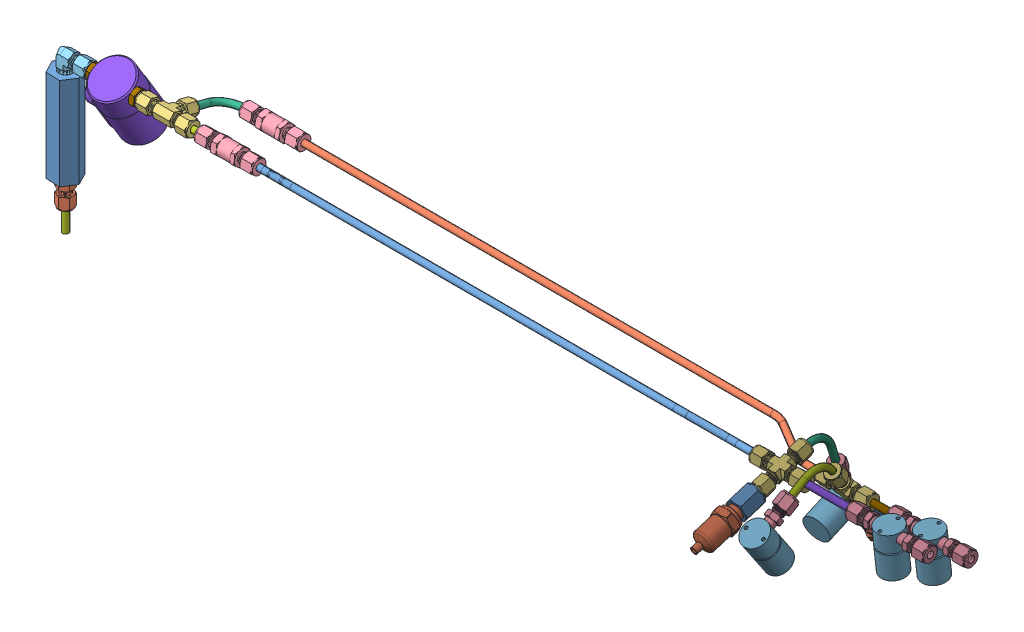
SolidWorks assembly Recovery Pneumatics, configuration Default. Lengths in mm.
Overall size (928.79 183.17 195.03).
34 component instances, 20 part files, 70 mates.
Components (placement in the parent):
- Inline Regulator-1: Inline Regulator [Default] at (0 145.161 0) x (-0.998761 0 -0.049763) z (0 -1 0) size (29.33 25.4 95.25)
- -4S -4MNPT-1: -4S -4MNPT [5182K111] at (0 22.86 0) x (0.584753 0 0.811212) z (0 -1 0) size (14.29 16.5 37.85)
- -4S Tee-1: -4S Tee [5182K434] at (78.3336 157.734 0) x (0 0.968728 -0.248124) z (-1 0 0) size (14.29 35.17 53.85)
- Check Valve -4S-2: Check Valve -4S [45385K54] at (155.8036 142.2302 -60.53) x (0 -0.278871 -0.960328) z (-1 0 0) size (15.88 18.33 60.45)
- -4S -4MNPT Elbow-3: -4S -4MNPT Elbow [5929K75] at (26.924 157.734 0) x (0 0 1) z (1 0 0) size (14.48 32.03 34.26)
- -4 Bend90 R.75 Recovery-2: -4 Bend90 R.75 Recovery [Default] at (122.7853 142.2302 -60.53) x (0 0.248124 0.968728) z (0 -0.968728 0.248124) size (53.97 38.74 6.35)
- -4 B2B Short-4: -4 B2B Short [Default] at (155.0416 157.734 0) x (0 1 0) z (0 0 1) size (6.35 38.1 6.35)
- Check Valve -4S-3: Check Valve -4S [45385K54] at (170.0276 157.734 0) x (0 0.175228 0.984528) z (-1 0 0) size (15.88 18.33 60.45)
- -4 B2B Short-5: -4 B2B Short [Default] at origin size (6.35 38.1 6.35)
- HP Solenoid -4FNPT-1: HP Solenoid -4FNPT [1190N23] at (52.6288 157.734 0) x (0 0.517885 -0.85545) z (-1 0 0) size (41.45 73.66 101.05)
- -4FS -4MNPT-1: -4FS -4MNPT [5929K622] at (11.684 157.734 0) x (0 0 1) z (-1 0 0) size (14.29 16.5 35.56)
- -4FS -4MNPT-2: -4FS -4MNPT [5929K622] at (93.5736 157.734 0) x (0 -0.924225 -0.381849) z (1 0 0) size (14.29 16.5 35.56)
- -4S -6FNPT-1: -4S -6FNPT [5182K287] at (738.088 152.0363 8.9048) x (0.794831 -0.579579 -0.179812) z (0 0.296312 -0.955091) size (19.05 22 37.77)
- PT -4MNPT-1: PT -4MNPT [Default] at (738.088 136.2926 59.6509) x (0 0.296312 -0.955091) z (-0.840318 0.517749 0.160629) size (56.32 25.42 22.23)
- -4S Cross-1: -4S Cross [5182K766] at (738.088 163.4764 -27.9694) x (0 -0.955091 -0.296312) z (0 0.296312 -0.955091) size (14.29 53.85 53.85)
- -4S -6FNPT-2: -4S -6FNPT [5182K287] at (772.5677 129.6883 -41.7795) x (0.463473 -0.49232 0.736759) z (0 0.831452 0.555596) size (19.05 22 37.77)
- PT -4MNPT-2: PT -4MNPT [Default] at (772.5677 85.5113 -71.2995) x (0 0.831452 0.555596) z (0.508115 0.478529 -0.716121) size (56.32 25.42 22.23)
- -4S Cross-2: -4S Cross [5182K766] at (772.5677 161.789 -20.329) x (0 0.555596 -0.831452) z (0 0.831452 0.555596) size (14.29 53.85 53.85)
- -4S -2MNPT-1: -4S -2MNPT [5182K807] at (810.732 155.4984 -2.2545) x (0 0 1) z (-1 0 0) size (14.29 16.5 32.77)
- Solenoid -2FNPT-1: Solenoid -2FNPT [Default] at (849.848 161.8092 -1.5493) x (0 0.111058 -0.993814) z (-1 0 0) size (25.4 43.18 25.4)
- -4 Bend90 R.75 RecovVent1-1: -4 Bend90 R.75 RecovVent1 [Default] at (738.088 164.3038 -30.6363) x (0.009447 -0.955048 -0.296299) z (0.999955 0.009023 0.002799) size (53.97 38.74 6.35)
- -4 Bend90 R.75 RecovVent2-1: -4 Bend90 R.75 RecovVent2 [Default] at (772.5677 164.1107 -18.7776) x (-0.046359 -0.554999 0.830558) z (-0.998925 0.025757 -0.038545) size (53.97 38.74 6.35)
- -4 RecovCustom1-1: -4 RecovCustom1 [Default] at (749.772 155.4984 -2.2545) x (0 -1 0) z (0 0 1) size (6.35 76.2 6.35)
- -4 RecovCustom2-1: -4 RecovCustom2 [Default] at (784.2517 139.403 -35.2879) x (0 -0.992135 0.125175) z (0 0.125175 0.992135) size (6.35 50.8 6.35)
- Solenoid -2FNPT-2: Solenoid -2FNPT [Default] at (858.9277 145.7137 -34.5826) x (0 0.111058 -0.993814) z (-1 0 0) size (25.4 43.18 25.4)
- -4S -2MNPT-2: -4S -2MNPT [5182K807] at (819.8117 139.403 -35.2879) x (0 0 1) z (-1 0 0) size (14.29 16.5 32.77)
- Solenoid -2FNPT-3: Solenoid -2FNPT [Default] at (768.9978 142.5208 56.5068) x (0.99878 -0.011601 0.047997) z (0.046359 0.554999 -0.830558) size (25.4 43.18 25.4)
- -4S -2MNPT-3: -4S -2MNPT [5182K807] at (770.9192 158.9483 20.4954) x (-0.571243 -0.667355 -0.477827) z (0.046359 0.554999 -0.830558) size (14.29 16.5 32.77)
- Solenoid -2FNPT-4: Solenoid -2FNPT [Default] at (738.2422 100.0477 -75.5468) x (-0.99618 -0.034714 0.080129) z (-0.009447 0.955048 0.296299) size (25.4 43.18 25.4)
- -4S -2MNPT-4: -4S -2MNPT [5182K807] at (738.4239 135.5359 -57.9133) x (0.766144 0.197332 -0.611623) z (-0.009447 0.955048 0.296299) size (14.29 16.5 32.77)
- -4 Recov Resevoir 1-1: -4 Recov Resevoir 1 [Default] at (200.2144 147.3252 -10.4972) x (1 0 0) z (0 0.710089 -0.704112) size (541.39 28.58 6.35)
- -4 Recov Resevoir 2-1: -4 Recov Resevoir 2 [Default] at (729.1237 139.403 -35.2879) x (1 0 0) z (0 -0.993786 -0.11131) size (590.09 31.75 6.35)
- -4S -2MNPT-5: -4S -2MNPT [5182K807] at (901.0917 139.403 -35.2879) x (0 -0.063281 -0.997996) z (1 0 0) size (14.29 16.5 32.77)
- -4S -2MNPT-6: -4S -2MNPT [5182K807] at (892.012 155.4984 -2.2545) x (0 -0.063281 -0.997996) z (1 0 0) size (14.29 16.5 32.77)
Mates (geometry in assembly coordinates):
- Distance5: distance = 6.35 mm anti-aligned: plane of InlineRegulator-1 through (0 67.056 0) normal (0 -1 0); plane of -4S -4MNPT-1 through (0 60.706 0) normal (0 1 0)
- Concentric7: concentric aligned: cylinder of InlineRegulator-1 through (0 67.056 0) axis (0 -1 0) radius 6.858; cylinder of -4S -4MNPT-1 through (0 22.86 0) axis (0 -1 0) radius 4.6228
- Distance8: distance = 6.35 mm anti-aligned: plane of -4S -4MNPT Elbow-3 through (0 134.366 0) normal (0 -1 0); plane of InlineRegulator-1 through (0 128.016 0) normal (0 1 0)
- Concentric26: concentric aligned: cylinder of InlineRegulator-1 through (0 128.016 0) axis (0 1 0) radius 6.858; cylinder of -4S -4MNPT Elbow-3 through (0 162.8866 0) axis (0 1 0) radius 4.6228
- Coincident34: coincident anti-aligned: plane of Check Valve -4S-2 through (140.8176 139.1812 -59.6446) normal (-1 0 0); plane of -4 Bend90 R.75 Recovery-2 through (140.8176 142.2302 -60.53) normal (1 0 0)
- Concentric28: concentric aligned: cylinder of Check Valve -4S-2 through (125.5776 142.2302 -60.53) axis (-1 0 0) radius 2.3749; cylinder of -4 Bend90 R.75 Recovery-2 through (140.8176 142.2302 -60.53) axis (-1 0 0) radius 2.286
- Coincident35: coincident anti-aligned: plane of -4S Tee-1 through (108.4326 154.8349 -11.3186) normal (0 -0.248124 -0.968728); plane of -4 Bend90 R.75 Recovery-2 through (105.2576 154.8349 -11.3186) normal (0 0.248124 0.968728)
- Concentric29: concentric anti-aligned: cylinder of -4S Tee-1 through (105.2576 151.0535 -26.082) axis (0 -0.248124 -0.968728) radius 2.3749; cylinder of -4 Bend90 R.75 Recovery-2 through (105.2576 146.957 -42.0757) axis (0 0.248124 0.968728) radius 2.286
- Coincident36: coincident anti-aligned: plane of -4S Tee-1 through (116.9416 158.5218 3.0757) normal (1 0 0); plane of -4 B2B Short-4 through (116.9416 157.734 0) normal (-1 0 0)
- Concentric30: concentric anti-aligned: cylinder of -4S Tee-1 through (78.3336 157.734 0) axis (-1 0 0) radius 2.3749; cylinder of -4 B2B Short-4 through (116.9416 157.734 0) axis (1 0 0) radius 2.286
- Concentric31: concentric anti-aligned: cylinder of -4 B2B Short-4 through (116.9416 157.734 0) axis (1 0 0) radius 2.286; cylinder of Check Valve -4S-3 through (139.8016 157.734 0) axis (-1 0 0) radius 2.3749
- Coincident37: coincident anti-aligned: plane of -4 B2B Short-4 through (155.0416 157.734 0) normal (1 0 0); plane of Check Valve -4S-3 through (155.0416 160.8599 -0.5563) normal (-1 0 0)
- Coincident47: coincident anti-aligned: plane of -4S -4MNPT-1 through (-2.5756 38.1 1.8566) normal (0 -1 0); plane of -4 B2B Short-5 through (0 38.1 0) normal (0 1 0)
- Concentric41: concentric aligned: cylinder of -4S -4MNPT-1 through (0 22.86 0) axis (0 -1 0) radius 2.3749; cylinder of -4 B2B Short-5 through (0 38.1 0) axis (0 -1 0) radius 2.286
- Concentric42: concentric aligned: cylinder of -4 B2B Short-5 through (0 38.1 0) axis (0 -1 0) radius 2.286
- Coincident49: coincident: plane of -4 B2B Short-5 through (0 0 0) normal (0 -1 0)
- Coincident51: coincident anti-aligned: plane of -4S -4MNPT Elbow-3 through (11.684 154.559 0) normal (1 0 0); plane of -4FS -4MNPT-1 through (11.684 157.734 0) normal (-1 0 0)
- Concentric43: concentric anti-aligned: cylinder of -4S -4MNPT Elbow-3 through (26.924 157.734 0) axis (1 0 0) radius 2.3749; cylinder of -4FS -4MNPT-1 through (11.684 157.734 0) axis (-1 0 0) radius 1.651
- Coincident52: coincident anti-aligned: plane of HP Solenoid -4FNPT-1 through (58.0136 157.734 0) normal (1 0 0); plane of -4FS -4MNPT-2 through (58.0136 157.734 0) normal (-1 0 0)
- Concentric44: concentric anti-aligned: cone of HP Solenoid -4FNPT-1 through (71.9836 157.734 0) axis (-1 0 0); cylinder of -4FS -4MNPT-2 through (93.5736 157.734 0) axis (1 0 0) radius 4.6228
- Concentric45: concentric anti-aligned: cone of HP Solenoid -4FNPT-1 through (33.274 157.734 0) axis (1 0 0); cylinder of -4FS -4MNPT-1 through (11.684 157.734 0) axis (-1 0 0) radius 4.6228
- Coincident55: coincident anti-aligned: plane of HP Solenoid -4FNPT-1 through (47.244 157.734 0) normal (-1 0 0); plane of -4FS -4MNPT-1 through (47.244 157.734 0) normal (1 0 0)
- Coincident56: coincident anti-aligned: plane of -4S Tee-1 through (93.5736 156.9462 -3.0757) normal (-1 0 0); plane of -4FS -4MNPT-2 through (93.5736 157.734 0) normal (1 0 0)
- Concentric47: concentric anti-aligned: cylinder of -4S Tee-1 through (78.3336 157.734 0) axis (-1 0 0) radius 3.175; cylinder of -4FS -4MNPT-2 through (93.5736 157.734 0) axis (1 0 0) radius 1.651
- Coincident59: coincident aligned: circle of -4S -4FNPT-1; plane of PT -4MNPT-1 through (738.088 143.9967 34.8186) normal (0 0.296312 -0.955091)
- Concentric50: concentric aligned: cylinder of -4S -6FNPT-1 through (738.088 152.0363 8.9048) axis (0 0.296312 -0.955091) radius 4.6228; cylinder of PT -4MNPT-1 through (738.088 139.552 49.1449) axis (0 0.296312 -0.955091) radius 4
- Concentric52: concentric aligned: cylinder of -4S -6FNPT-1 through (738.088 152.0363 8.9048) axis (0 0.296312 -0.955091) radius 2.3876; cylinder of -4S Cross-1 through (738.088 163.4764 -27.9694) axis (0 0.296312 -0.955091) radius 2.3749
- Coincident61: coincident anti-aligned: plane of -4S -6FNPT-1 through (738.088 152.0363 8.9048) normal (0 0.296312 -0.955091); plane of -4S Cross-1 through (741.263 152.0363 8.9048) normal (0 -0.296312 0.955091)
- Coincident65: coincident anti-aligned: plane of -4S -6FNPT-2 through (772.5677 129.6883 -41.7795) normal (0 0.831452 0.555596); plane of -4S Cross-2 through (775.7427 129.6883 -41.7795) normal (0 -0.831452 -0.555596)
- Concentric57: concentric aligned: cylinder of -4S -6FNPT-2 through (772.5677 129.6883 -41.7795) axis (0 0.831452 0.555596) radius 2.3876; cylinder of -4S Cross-2 through (772.5677 161.789 -20.329) axis (0 0.831452 0.555596) radius 2.3749
- Concentric58: concentric aligned: cylinder of -4S -6FNPT-2 through (772.5677 129.6883 -41.7795) axis (0 0.831452 0.555596) radius 4.6228; cylinder of PT -4MNPT-2 through (772.5677 94.6573 -65.188) axis (0 0.831452 0.555596) radius 4
- Coincident67: coincident aligned: circle of -4S -4FNPT-2; plane of PT -4MNPT-2 through (772.5677 107.1291 -56.854) normal (0 0.831452 0.555596)
- Coincident69: coincident anti-aligned: plane of Solenoid -2FNPT-1 through (843.498 155.4984 -2.2545) normal (-1 0 0); plane of -4S -2MNPT-1 through (843.498 155.4984 -2.2545) normal (1 0 0)
- Concentric60: concentric anti-aligned: cylinder of Solenoid -2FNPT-1 through (837.147 155.4984 -2.2545) axis (1 0 0) radius 3.175; cylinder of -4S -2MNPT-1 through (810.732 155.4984 -2.2545) axis (-1 0 0) radius 3.4163
- Coincident70: coincident anti-aligned: plane of -4S Cross-1 through (734.913 158.9606 -13.4138) normal (0 0.296312 -0.955091); plane of -4 Bend90 R.75 RecovVent1-1 through (738.088 158.9606 -13.4138) normal (0 -0.296312 0.955091)
- Concentric61: concentric aligned: cylinder of -4S Cross-1 through (738.088 163.4764 -27.9694) axis (0 0.296312 -0.955091) radius 2.3749; cylinder of -4 Bend90 R.75 RecovVent1-1 through (738.088 158.9606 -13.4138) axis (0 0.296312 -0.955091) radius 2.286
- Concentric62: concentric aligned: cylinder of -4S Cross-2 through (772.5677 161.789 -20.329) axis (0 0.831452 0.555596) radius 2.3749; cylinder of -4 Bend90 R.75 RecovVent2-1 through (772.5677 149.1177 -28.7963) axis (0 0.831452 0.555596) radius 2.286
- Coincident71: coincident anti-aligned: plane of -4S Cross-2 through (769.3927 149.1177 -28.7963) normal (0 0.831452 0.555596); plane of -4 Bend90 R.75 RecovVent2-1 through (772.5677 149.1177 -28.7963) normal (0 -0.831452 -0.555596)
- Coincident72: coincident anti-aligned: plane of -4S Cross-1 through (749.772 156.4392 -5.2869) normal (1 0 0); plane of -4 RecovCustom1-1 through (749.772 155.4984 -2.2545) normal (-1 0 0)
- Concentric63: concentric anti-aligned: cylinder of -4S Cross-1 through (765.012 155.4984 -2.2545) axis (1 0 0) radius 2.3749; cylinder of -4 RecovCustom1-1 through (825.972 155.4984 -2.2545) axis (-1 0 0) radius 2.286
- Coincident73: coincident anti-aligned: plane of -4S Cross-2 through (784.2517 142.0428 -33.5239) normal (1 0 0); plane of -4 RecovCustom2-1 through (784.2517 139.403 -35.2879) normal (-1 0 0)
- Concentric64: concentric anti-aligned: cylinder of -4S Cross-2 through (799.4917 139.403 -35.2879) axis (1 0 0) radius 2.3749; cylinder of -4 RecovCustom2-1 through (835.0517 139.403 -35.2879) axis (-1 0 0) radius 2.286
- Concentric65: concentric anti-aligned: cylinder of Solenoid -2FNPT-2 through (846.2267 139.403 -35.2879) axis (1 0 0) radius 3.175; cylinder of -4S -2MNPT-2 through (819.8117 139.403 -35.2879) axis (-1 0 0) radius 3.4163
- Coincident74: coincident anti-aligned: plane of Solenoid -2FNPT-2 through (852.5777 139.403 -35.2879) normal (-1 0 0); plane of -4S -2MNPT-2 through (852.5777 139.403 -35.2879) normal (1 0 0)
- Concentric66: concentric anti-aligned: cylinder of Solenoid -2FNPT-3 through (769.6946 144.2881 42.4346) axis (-0.046359 -0.554999 0.830558) radius 3.175; cylinder of -4S -2MNPT-3 through (770.9192 158.9483 20.4954) axis (0.046359 0.554999 -0.830558) radius 3.4163
- Coincident75: coincident anti-aligned: plane of Solenoid -2FNPT-3 through (769.4002 140.7633 47.7094) normal (0.046359 0.554999 -0.830558); plane of -4S -2MNPT-3 through (769.4002 140.7633 47.7094) normal (-0.046359 -0.554999 0.830558)
- Concentric67: concentric anti-aligned: cylinder of Solenoid -2FNPT-4 through (738.6735 110.3083 -65.74) axis (0.009447 -0.955048 -0.296299) radius 3.175; cylinder of -4S -2MNPT-4 through (738.4239 135.5359 -57.9133) axis (-0.009447 0.955048 0.296299) radius 3.4163
- Coincident76: coincident anti-aligned: plane of Solenoid -2FNPT-4 through (738.7335 104.2428 -67.6218) normal (-0.009447 0.955048 0.296299); plane of -4S -2MNPT-4 through (738.7335 104.2428 -67.6218) normal (0.009447 -0.955048 -0.296299)
- Coincident77: coincident anti-aligned: plane of -4 RecovCustom2-1 through (835.0517 139.403 -35.2879) normal (1 0 0); plane of -4S -2MNPT-2 through (835.0517 142.578 -35.2879) normal (-1 0 0)
- Concentric68: concentric aligned: cylinder of -4 RecovCustom2-1 through (835.0517 139.403 -35.2879) axis (-1 0 0) radius 2.286; cylinder of -4S -2MNPT-2 through (819.8117 139.403 -35.2879) axis (-1 0 0) radius 2.3749
- Coincident78: coincident anti-aligned: plane of -4S -2MNPT-1 through (825.972 158.6734 -2.2545) normal (-1 0 0); plane of -4 RecovCustom1-1 through (825.972 155.4984 -2.2545) normal (1 0 0)
- Concentric69: concentric aligned: cylinder of -4S -2MNPT-1 through (810.732 155.4984 -2.2545) axis (-1 0 0) radius 2.3749; cylinder of -4 RecovCustom1-1 through (825.972 155.4984 -2.2545) axis (-1 0 0) radius 2.286
- Concentric70: concentric anti-aligned: cylinder of -4 Bend90 R.75 RecovVent1-1 through (738.268 151.3038 -53.0214) axis (0.009447 -0.955048 -0.296299) radius 2.286; cylinder of -4S -2MNPT-4 through (738.4239 135.5359 -57.9133) axis (-0.009447 0.955048 0.296299) radius 3.175
- Coincident79: coincident anti-aligned: plane of -4 Bend90 R.75 RecovVent1-1 through (738.5679 120.981 -62.4289) normal (0.009447 -0.955048 -0.296299); plane of -4S -2MNPT-4 through (736.5277 121.6834 -64.7579) normal (-0.009447 0.955048 0.296299)
- Coincident80: coincident anti-aligned: plane of -4 Bend90 R.75 RecovVent2-1 through (770.2127 150.4902 33.1531) normal (-0.046359 -0.554999 0.830558); plane of -4S -2MNPT-3 through (767.6108 152.0669 34.0615) normal (0.046359 0.554999 -0.830558)
- Concentric71: concentric anti-aligned: cylinder of -4 Bend90 R.75 RecovVent2-1 through (771.6846 168.1114 6.7828) axis (-0.046359 -0.554999 0.830558) radius 2.286; cylinder of -4S -2MNPT-3 through (770.9192 158.9483 20.4954) axis (0.046359 0.554999 -0.830558) radius 2.3749
- Coincident85: coincident anti-aligned: plane of Check Valve -4S-2 through (170.7896 139.1812 -59.6446) normal (1 0 0); plane of -4 Recov Resevoir 2-1 through (170.7896 142.2302 -60.53) normal (-1 0 0)
- Concentric76: concentric anti-aligned: cylinder of Check Valve -4S-2 through (125.5776 142.2302 -60.53) axis (-1 0 0) radius 2.3749; cylinder of -4 Recov Resevoir 2-1 through (170.7896 142.2302 -60.53) axis (1 0 0) radius 3.175
- Coincident86: coincident anti-aligned: plane of -4S Cross-2 through (760.8837 136.7631 -37.0519) normal (-1 0 0); plane of -4 Recov Resevoir 2-1 through (760.8837 139.403 -35.2879) normal (1 0 0)
- Concentric77: concentric anti-aligned: cylinder of -4S Cross-2 through (745.6437 139.403 -35.2879) axis (-1 0 0) radius 3.175; cylinder of -4 Recov Resevoir 2-1 through (729.1237 139.403 -35.2879) axis (1 0 0) radius 2.286
- Coincident88: coincident anti-aligned: plane of Solenoid -2FNPT-1 through (859.246 155.4984 -2.2545) normal (1 0 0); plane of -4S -2MNPT-6 through (859.246 155.4984 -2.2545) normal (-1 0 0)
- Concentric79: concentric anti-aligned: cylinder of Solenoid -2FNPT-1 through (862.549 155.4984 -2.2545) axis (-1 0 0) radius 3.175; cylinder of -4S -2MNPT-6 through (892.012 155.4984 -2.2545) axis (1 0 0) radius 3.4163
- Coincident89: coincident anti-aligned: plane of Solenoid -2FNPT-2 through (868.3257 139.403 -35.2879) normal (1 0 0); plane of -4S -2MNPT-5 through (868.3257 139.403 -35.2879) normal (-1 0 0)
- Concentric80: concentric anti-aligned: cylinder of Solenoid -2FNPT-2 through (871.6287 139.403 -35.2879) axis (-1 0 0) radius 3.175; cylinder of -4S -2MNPT-5 through (901.0917 139.403 -35.2879) axis (1 0 0) radius 3.4163
- Coincident90: coincident anti-aligned: plane of Check Valve -4S-3 through (185.0136 160.8599 -0.5563) normal (1 0 0); plane of -4 Recov Resevoir 1-1 through (185.0136 157.734 0) normal (-1 0 0)
- Concentric81: concentric anti-aligned: cylinder of Check Valve -4S-3 through (139.8016 157.734 0) axis (-1 0 0) radius 2.3749; cylinder of -4 Recov Resevoir 1-1 through (185.0136 157.734 0) axis (1 0 0) radius 2.286
- Coincident91: coincident anti-aligned: plane of -4S Cross-1 through (726.404 154.5577 0.7779) normal (-1 0 0); plane of -4 Recov Resevoir 1-1 through (726.404 155.4984 -2.2545) normal (1 0 0)
- Concentric82: concentric anti-aligned: cylinder of -4S Cross-1 through (711.164 155.4984 -2.2545) axis (-1 0 0) radius 2.3749; cylinder of -4 Recov Resevoir 1-1 through (693.4084 155.4984 -2.2545) axis (1 0 0) radius 2.286
- Parallel1: parallel aligned: cylinder of -4 Recov Resevoir 1-1 through (248.5136 171.1473 13.5272) axis (1 0 0) radius 3.175
- Parallel2: parallel aligned: cylinder of -4 Recov Resevoir 2-1 through (170.7896 142.2302 -60.53) axis (1 0 0) radius 3.175
